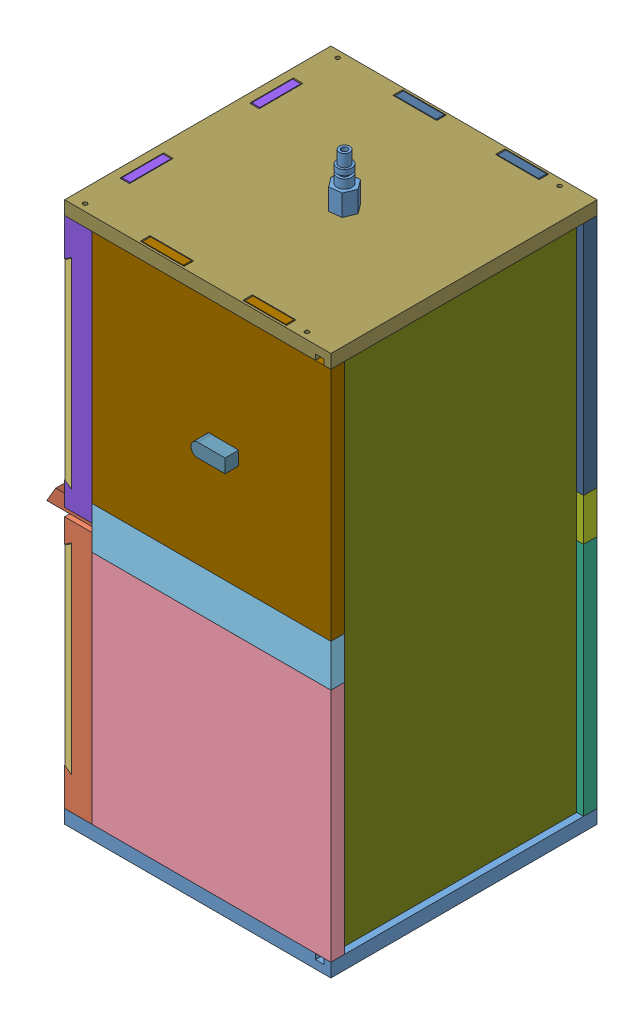
SolidWorks assembly CamaraContaminacaoVer2, configuration Valor predeterminado. Lengths in mm.
Overall size (211.3 433 220).
20 component instances, 19 part files, 52 mates.
Components (placement in the parent):
- Inferior-1: Inferior [Valor predeterminado] at (3.5979 -10.1969 195) size (195 15 195)
- TraseiraMod-1: TraseiraMod [Valor predeterminado] at (-93.9021 92.3031 195) x (0 0 -1) z (1 0 0) size (195 195 20)
- PortaTraseira-1: PortaTraseira [Valor predeterminado] at (-91.2021 97.023 102.5) x (0 0 1) z (-1 0 0) size (190 146.44 4.6)
- LaterialEsqInf-1: LaterialEsqInf [Valor predeterminado] at (13.5979 86.0531 282.5) size (185 192.5 10)
- LateralEsqCen-1: LateralEsqCen [Valor predeterminado] at (13.5979 187.8031 282.5) size (175 31 10)
- LaterialDirInf-1: LaterialDirInf [Valor predeterminado] at (13.5979 86.0531 97.5) size (185 192.5 10)
- LateralDirCen-1: LateralDirCen [Valor predeterminado] at (13.5979 187.8031 97.5) size (175 31 10)
- TraseiraModSup-1: TraseiraModSup [Valor predeterminado] at (-93.9021 283.3031 195) x (0 0 -1) z (1 0 0) size (195 195 20)
- PortaTraseira-2: PortaTraseira [Valor predeterminado] at (-91.2021 278.023 102.5) x (0 0 1) z (-1 0 0) size (190 146.44 4.6)
- LaterialEsqSup-1: LaterialEsqSup [Valor predeterminado] at (13.5979 289.5531 292.5) x (1 0 0) z (0 0 -1) size (185 192.5 10)
- LaterialDirSup-1: LaterialDirSup [Valor predeterminado] at (13.5979 289.5531 107.5) x (1 0 0) z (0 0 -1) size (185 192.5 10)
- Divisoria-1: Divisoria [Valor predeterminado] at (-110.2021 187.6031 195.1713) x (0 0 -1) z (1 0 0) size (188.14 4.6 200)
- Superior-2: Superior [Valor predeterminado] at (3.5979 385.8031 195) x (1 0 0) z (0 0 -1) size (195 10 195)
- Recipiente-1: Recipiente [Valor predeterminado] at (13.5979 278.3031 195) x (0 0 1) z (-1 0 0) size (30 25 30)
- Barra-1: Barra [Valor predeterminado] at (13.5979 285.8031 82.5) size (25 10 220)
- SuporteAmostraCilindrico-1: SuporteAmostraCilindrico [Valor predeterminado] at (13.4979 -0.1969 194.9) size (50 10 50)
- Vidro-1: Vidro [Valor predeterminado] at (89.8979 187.8031 195) x (0 0 -1) z (1 0 0) size (185 384 6)
- Amostra-1: Amostra [Valor predeterminado] at (13.4979 9.8031 194.9) size (15.5 7 15.5)
- Espigao1_4x5_16-1: Espigao1_4x5_16 [Valor predeterminado] at (13.5979 376.8031 195) x (0.999869 0 -0.016206) z (0.016206 0 0.999869) size (15.7 37.5 13.6)
- PinoEngateRapidoRoscaFemea1_4-1: PinoEngateRapidoRoscaFemea1_4 [Valor predeterminado] at (13.5979 385.8031 195) x (0.992556 0 -0.12179) z (0.12179 0 0.992556) size (17.8 37 15.42)
Mates (geometry in assembly coordinates):
- Coincidente1: coincident anti-aligned: plane of Inferior-1 through (3.5979 -0.1969 195) normal (0 1 0); plane of TraseiraMod-1 through (-73.9021 -0.1969 97.5) normal (0 -1 0)
- Coincidente2: coincident aligned: plane of Inferior-1 through (101.0979 -0.1969 292.5) normal (0 0 1); plane of TraseiraMod-1 through (-73.9021 -0.1969 292.5) normal (0 0 1)
- Coincidente3: coincident aligned: plane of Inferior-1 through (-93.9021 -0.1969 292.5) normal (-1 0 0); plane of TraseiraMod-1 through (-93.9021 92.3031 195) normal (-1 0 0)
- Coincidente5: coincident anti-aligned: line of TraseiraMod-1 through (-88.9021 23.8021 102.5) axis (0 0 1); line of PortaTraseira-1 through (-88.9021 23.8021 292.5) axis (0 0 -1)
- Paralelo2: parallel anti-aligned: plane of TraseiraMod-1 through (-93.9021 167.3031 102.5) normal (0.573576 -0.819152 0); plane of PortaTraseira-1 through (-124.8481 145.0744 292.5) normal (-0.573576 0.819152 0)
- DistânciaLimite1: limit distance = 0 mm anti-aligned: plane of PortaTraseira-1 through (-91.2021 97.023 102.5) normal (0 0 -1); plane of TraseiraMod-1 through (-93.9021 92.3031 102.5) normal (0 0 1)
- Coincidente9: coincident anti-aligned: plane of Inferior-1 through (3.5979 -0.1969 195) normal (0 1 0); plane of LaterialEsqInf-1 through (101.0979 -0.1969 292.5) normal (0 -1 0)
- Coincidente10: coincident anti-aligned: plane of TraseiraMod-1 through (-73.9021 92.3031 195) normal (1 0 0); plane of LaterialEsqInf-1 through (-73.9021 -0.1969 292.5) normal (-1 0 0)
- Coincidente11: coincident aligned: plane of TraseiraMod-1 through (-73.9021 -0.1969 292.5) normal (0 0 1); plane of LaterialEsqInf-1 through (13.5979 86.0531 292.5) normal (0 0 1)
- Coincidente12: coincident anti-aligned: plane of LaterialEsqInf-1 through (101.0979 172.3031 292.5) normal (0 1 0); plane of LateralEsqCen-1 through (101.0979 172.3031 292.5) normal (0 -1 0)
- Coincidente13: coincident anti-aligned: plane of TraseiraMod-1 through (-73.9021 92.3031 195) normal (1 0 0); plane of LateralEsqCen-1 through (-73.9021 172.3031 292.5) normal (-1 0 0)
- Coincidente14: coincident aligned: plane of LaterialEsqInf-1 through (13.5979 86.0531 292.5) normal (0 0 1); plane of LateralEsqCen-1 through (13.5979 187.8031 292.5) normal (0 0 1)
- Coincidente15: coincident anti-aligned: plane of TraseiraMod-1 through (-73.9021 92.3031 195) normal (1 0 0); plane of LaterialDirInf-1 through (-73.9021 -0.1969 107.5) normal (-1 0 0)
- Coincidente16: coincident anti-aligned: plane of Inferior-1 through (3.5979 -0.1969 195) normal (0 1 0); plane of LaterialDirInf-1 through (101.0979 -0.1969 107.5) normal (0 -1 0)
- Coincidente17: coincident aligned: plane of Inferior-1 through (101.0979 -0.1969 97.5) normal (0 0 -1); plane of LaterialDirInf-1 through (13.5979 86.0531 97.5) normal (0 0 -1)
- Coincidente18: coincident anti-aligned: plane of TraseiraMod-1 through (-73.9021 92.3031 195) normal (1 0 0); plane of LateralDirCen-1 through (-73.9021 172.3031 107.5) normal (-1 0 0)
- Coincidente19: coincident anti-aligned: plane of LaterialDirInf-1 through (101.0979 172.3031 107.5) normal (0 1 0); plane of LateralDirCen-1 through (101.0979 172.3031 107.5) normal (0 -1 0)
- Coincidente21: coincident aligned: plane of LaterialDirInf-1 through (13.5979 86.0531 97.5) normal (0 0 -1); plane of LateralDirCen-1 through (13.5979 187.8031 97.5) normal (0 0 -1)
- Coincidente22: coincident anti-aligned: plane of LateralDirCen-1 through (-73.9021 172.3031 107.5) normal (-1 0 0); plane of TraseiraModSup-1 through (-73.9021 283.3031 195) normal (1 0 0)
- Coincidente23: coincident aligned: plane of LateralEsqCen-1 through (13.5979 187.8031 292.5) normal (0 0 1); plane of TraseiraModSup-1 through (-73.9021 190.8031 292.5) normal (0 0 1)
- Concêntrico1: concentric aligned: cylinder of LateralEsqCen-1 through (-65.9021 198.3031 287.5) axis (-1 0 0) radius 1.5; cylinder of TraseiraModSup-1 through (-73.9021 198.3031 287.5) axis (-1 0 0) radius 1.5
- Coincidente24: coincident anti-aligned: line of TraseiraModSup-1 through (-88.9021 204.8021 102.5) axis (0 0 1); line of PortaTraseira-2 through (-88.9021 204.8021 292.5) axis (0 0 -1)
- Paralelo4: parallel anti-aligned: plane of TraseiraModSup-1 through (-93.9021 348.3031 102.5) normal (0.573576 -0.819152 0); plane of PortaTraseira-2 through (-124.8481 326.0744 292.5) normal (-0.573576 0.819152 0)
- DistânciaLimite2: limit distance = 0 mm anti-aligned: plane of PortaTraseira-2 through (-91.2021 278.023 102.5) normal (0 0 -1); plane of TraseiraModSup-1 through (-93.9021 283.3031 102.5) normal (0 0 1)
- Coincidente27: coincident anti-aligned: plane of LateralEsqCen-1 through (101.0979 203.3031 292.5) normal (0 1 0); plane of LaterialEsqSup-1 through (101.0979 203.3031 282.5) normal (0 -1 0)
- Coincidente28: coincident anti-aligned: plane of TraseiraModSup-1 through (-73.9021 283.3031 195) normal (1 0 0); plane of LaterialEsqSup-1 through (-73.9021 375.8031 282.5) normal (-1 0 0)
- Coincidente29: coincident aligned: plane of TraseiraModSup-1 through (-73.9021 190.8031 292.5) normal (0 0 1); plane of LaterialEsqSup-1 through (13.5979 289.5531 292.5) normal (0 0 1)
- Coincidente30: coincident anti-aligned: plane of LateralDirCen-1 through (101.0979 203.3031 107.5) normal (0 1 0); plane of LaterialDirSup-1 through (101.0979 203.3031 97.5) normal (0 -1 0)
- Coincidente31: coincident anti-aligned: plane of TraseiraModSup-1 through (-73.9021 283.3031 195) normal (1 0 0); plane of LaterialDirSup-1 through (-73.9021 375.8031 97.5) normal (-1 0 0)
- Coincidente32: coincident aligned: plane of TraseiraModSup-1 through (-73.9021 190.8031 97.5) normal (0 0 -1); plane of LaterialDirSup-1 through (13.5979 289.5531 97.5) normal (0 0 -1)
- Coincidente33: coincident anti-aligned: plane of LateralDirCen-1 through (98.5151 185.3031 100.3593) normal (0 1 0); plane of Divisoria-1 through (89.7979 185.3031 195.1713) normal (0 -1 0)
- Distância3: distance = 0.4 mm: line of Divisoria-1 through (89.7979 185.3031 289.2407) axis (-1 0 0); line of LateralEsqCen-1 through (89.7979 185.3031 289.6407) axis (-1 0 0)
- DistânciaLimite3: limit distance = 0 mm aligned: plane of Divisoria-1 through (89.7979 187.6031 195.1713) normal (1 0 0); plane of LateralDirCen-1 through (89.7979 172.3031 102.5) normal (1 0 0)
- Coincidente36: coincident anti-aligned: plane of LaterialEsqSup-1 through (101.0979 375.8031 282.5) normal (0 1 0); plane of Superior-2 through (3.5979 375.8031 195) normal (0 -1 0)
- Coincidente37: coincident aligned: plane of TraseiraModSup-1 through (-93.9021 283.3031 195) normal (-1 0 0); plane of Superior-2 through (-93.9021 375.8031 97.5) normal (-1 0 0)
- Coincidente38: coincident aligned: plane of LaterialEsqSup-1 through (13.5979 289.5531 292.5) normal (0 0 1); plane of Superior-2 through (101.0979 375.8031 292.5) normal (0 0 1)
- Concêntrico4: concentric anti-aligned: cylinder of LaterialEsqSup-1 through (13.5979 285.8031 282.5) axis (0 0 1) radius 5.25; cylinder of Barra-1 through (13.5979 285.8031 302.5) axis (0 0 -1) radius 5
- Paralelo5: parallel anti-aligned: plane of LaterialDirSup-1 through (17.4479 289.5531 107.5) normal (-1 0 0); plane of Barra-1 through (17.0979 285.8031 302.5) normal (1 0 0)
- Concêntrico5: concentric anti-aligned: cylinder of Recipiente-1 through (13.5979 285.8031 180) axis (0 0 1) radius 5.3; cylinder of Barra-1 through (13.5979 285.8031 302.5) axis (0 0 -1) radius 5
- Coincidente42: coincident anti-aligned: plane of Inferior-1 through (3.5979 4.8031 200) normal (0 0 1); plane of SuporteAmostraCilindrico-1 through (13.4979 5.8031 200) normal (0 0 -1)
- Coincidente43: coincident anti-aligned: plane of Inferior-1 through (18.5979 4.8031 195) normal (1 0 0); plane of SuporteAmostraCilindrico-1 through (18.5979 5.8031 194.9) normal (-1 0 0)
- Coincidente44: coincident anti-aligned: plane of Inferior-1 through (3.5979 -0.1969 195) normal (0 1 0); plane of SuporteAmostraCilindrico-1 through (13.4979 -0.1969 194.9) normal (0 -1 0)
- Coincidente48: coincident anti-aligned: plane of LaterialEsqSup-1 through (13.5979 289.5531 287.5) normal (0 0 -1); plane of Vidro-1 through (95.8979 -4.1969 287.5) normal (0 0 1)
- Coincidente50: coincident anti-aligned: plane of Superior-2 through (3.5979 379.8031 195) normal (0 -1 0); plane of Vidro-1 through (95.8979 379.8031 102.5) normal (0 1 0)
- Coincidente51: coincident anti-aligned: plane of LaterialEsqSup-1 through (89.8979 375.8031 287.5) normal (1 0 0); plane of Vidro-1 through (89.8979 187.8031 195) normal (-1 0 0)
- DistânciaLimite4: limit distance = 0 mm anti-aligned: plane of Barra-1 through (33.5979 280.8031 292.5) normal (0 0 -1); plane of LaterialEsqSup-1 through (13.5979 289.5531 292.5) normal (0 0 1)
- Coincidente54: coincident anti-aligned: plane of Superior-2 through (3.5979 382.8031 195) normal (0 -1 0); plane of Espigao1_4x5_16-1 through (13.5979 382.8031 195) normal (0 1 0)
- Concêntrico7: concentric anti-aligned: cylinder of Superior-2 through (13.5979 375.8031 195) axis (0 1 0) radius 7; cylinder of Espigao1_4x5_16-1 through (13.5979 394.8031 195) axis (0 -1 0) radius 6.6
- Concêntrico8: concentric aligned: cylinder of Espigao1_4x5_16-1 through (13.5979 394.8031 195) axis (0 -1 0) radius 6.6; cylinder of PinoEngateRapidoRoscaFemea1_4-1 through (13.5979 399.5531 195) axis (0 -1 0) radius 5.5
- Coincidente57: coincident anti-aligned: plane of Superior-2 through (3.5979 385.8031 195) normal (0 1 0); plane of PinoEngateRapidoRoscaFemea1_4-1 through (13.5979 385.8031 195) normal (0 -1 0)
- Coincidente59: coincident: plane of SuporteAmostraCilindrico-1 through (13.4979 9.8031 194.9) normal (0 1 0); plane of Amostra-1 through (13.4979 9.8031 194.9) normal (0 -1 0)
- Concêntrico10: concentric aligned: circle of SuporteAmostraCilindrico-1; circle of Amostra-1
